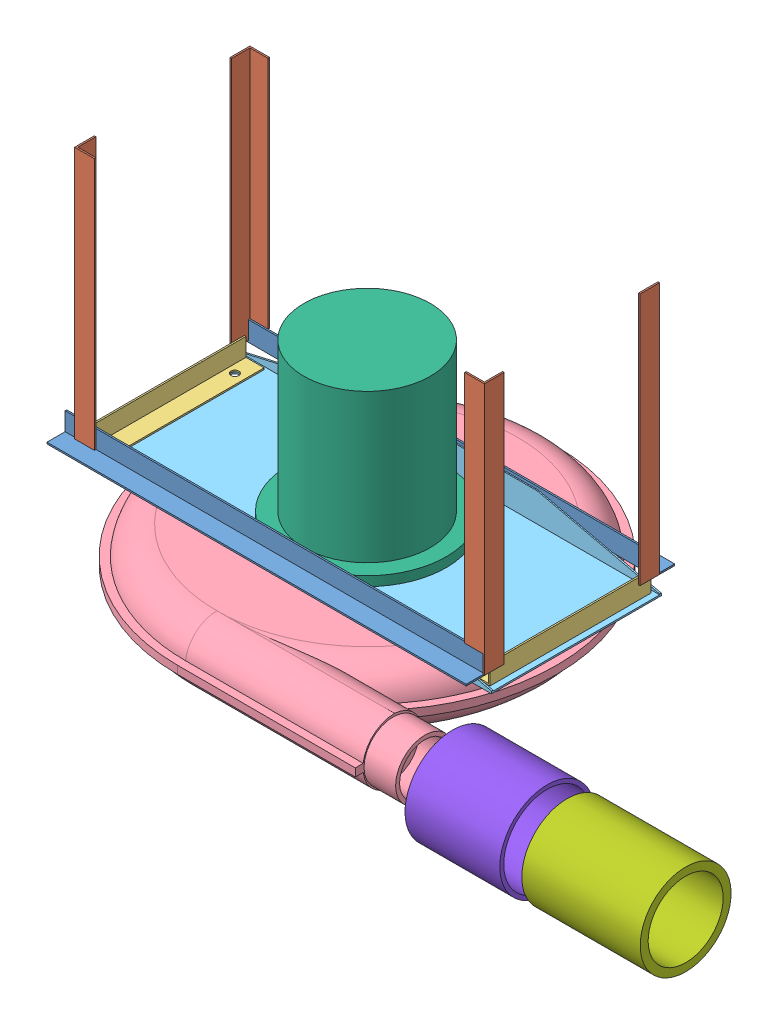
SolidWorks assembly ВытяжкаСБАЛТ, configuration По умолчанию. Lengths in mm.
Overall size (868.88 463.43 516.43).
15 component instances, 8 part files, 3 mates.
Components (placement in the parent):
- СбПодставкаАлт-1: СбПодставкаАлт [По умолчанию] at (217.9189 372.3329 327.7459) size (533 337 264)
  - ВПбоковина-1: ВПбоковина [По умолчанию] at (-6.0749 296.9287 359.6698) size (531 25 25)
  - ВПребро-1: ВПребро [По умолчанию] at (526.9251 618.9287 577.6698) x (0 -1 0) z (1 0 0) size (320 25 25)
  - ВПтыл-1: ВПтыл [По умолчанию] at (9.9251 281.9287 568.6698) x (0 0 -1) z (0 -1 0) size (204 25 25)
  - ВПребро-2: ВПребро [По умолчанию] at (7.9251 618.9287 355.6698) x (0 -1 0) z (-1 0 0) size (320 25 25)
  - ВПтыл-2: ВПтыл [По умолчанию] at (524.9251 281.9287 364.6698) x (0 0 1) z (0 -1 0) size (204 25 25)
  - ВПбоковина-2: ВПбоковина [По умолчанию] at (-6.0749 296.9287 573.6698) x (1 0 0) z (0 -1 0) size (531 25 25)
  - ВПребро-3: ВПребро [По умолчанию] at (7.9251 618.9287 577.6698) x (0 -1 0) z (0 0 1) size (320 25 25)
  - ВПребро-4: ВПребро [По умолчанию] at (526.9251 298.9287 355.6698) x (0 1 0) z (1 0 0) size (320 25 25)
- Вытяжка-1: Вытяжка [По умолчанию] at (485.344 607.2615 794.4157) x (-1 0 0) z (0 0 -1) size (860.38 326.43 516.43)
  - Улитка-1: Улитка [По умолчанию] at origin size (505 110.1 480)
  - Крепление-1: Крепление [По умолчанию] at (-265 45 2.5) size (530 38.5 215)
  - Мотор-1: Мотор [По умолчанию] at (0 247 0) x (-0.825077 0 -0.56502) z (-0.56502 0 0.825077) size (200 200 200)
  - Асбестовая-1: Асбестовая [По умолчанию] at (-595.3778 5 -192) x (0 -0.991749 -0.128194) z (0 -0.128194 0.991749) size (115 150 115)
  - Гофра-1: Гофра [По умолчанию] at (-420.0302 5 -192) x (0 -0.774417 -0.632675) z (0 -0.632675 0.774417) size (120 120 120)
Mates (geometry in assembly coordinates):
- Концентричный2: concentric anti-aligned: cylinder of СбПодставкаАлт-1/ВПтыл-2 through (730.344 679.2615 871.9157) axis (0 -1 0) radius 5; cylinder of Вытяжка-1/Крепление-1 through (730.344 652.2615 871.9157) axis (0 1 0) radius 5
- Совпадение7: coincident anti-aligned: plane of СбПодставкаАлт-1/ВПтыл-1 through (252.844 654.2615 692.4157) normal (0 -1 0); plane of Вытяжка-1/Крепление-1 through (220.344 654.2615 686.9157) normal (0 1 0)
- Параллельность1: parallel aligned: plane of СбПодставкаАлт-1/ВПтыл-1 through (227.844 654.2615 896.4157) normal (0 0 1); plane of Вытяжка-1/Крепление-1 through (220.344 652.2615 901.9157) normal (0 0 1)
